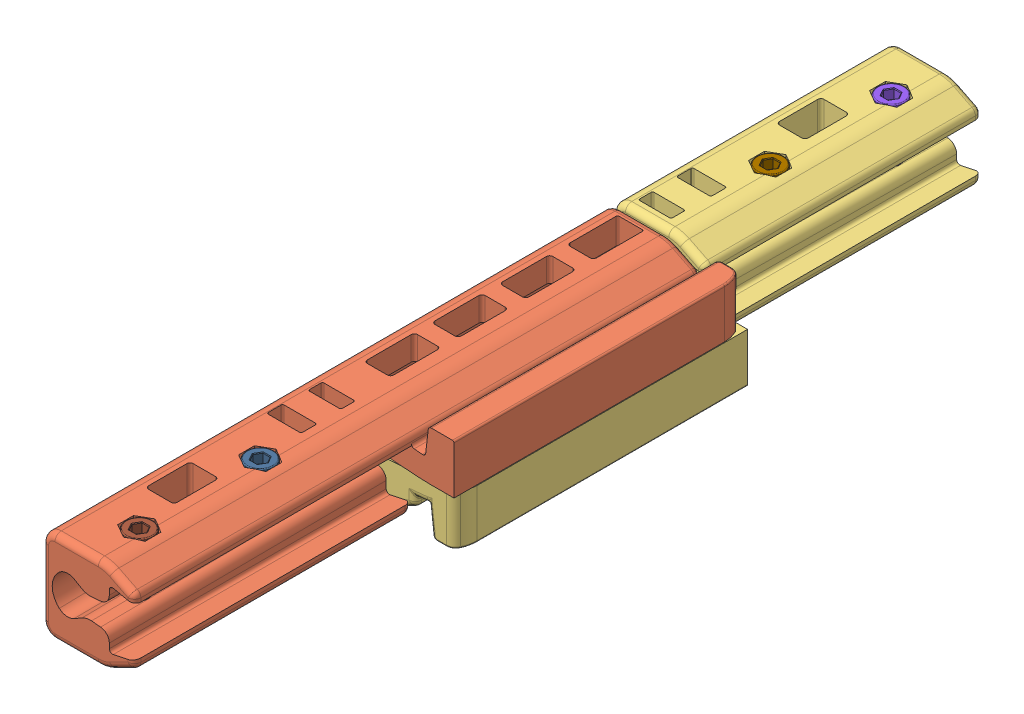
SolidWorks assembly S0737695412, configuration Default. Lengths in mm.
Overall size (43.41 31.2 267.09).
11 component instances, 11 part files, 19 mates.
Components (placement in the parent):
- 34796-CATALOGO-1: 34796-CATALOGO [Alapért.] at (4.7869 26.3916 0) size (5 5 189.3)
- 688102-1-1: 688102-1 [Alapért.] at (4.7869 26.3916 -24.7392) size (43.41 30.1 179.33)
- 688102-1_1-1: 688102-1_1 [Alapért.] at (4.7869 26.3916 0) size (43.41 30.1 179.33)
- M5-NORMALE-1: M5-NORMALE [Alapért.] at (4.7869 26.3416 -24.7392) size (8 4 9.24)
- M5-NORMALE_1-1: M5-NORMALE_1 [Alapért.] at (4.7869 26.3416 -24.7392) size (8 4 9.24)
- M5-NORMALE_2-1: M5-NORMALE_2 [Alapért.] at (4.7869 26.3916 0) size (8 4 9.24)
- M5-NORMALE_3-1: M5-NORMALE_3 [Alapért.] at (4.7869 26.3916 0) size (8 4 9.24)
- VTC_EI_M5X25_ZIN-1: VTC_EI_M5X25_ZIN [Alapért.] at (4.7869 26.3916 0) size (8.5 30 8.5)
- VTC_EI_M5X25_ZIN_1-1: VTC_EI_M5X25_ZIN_1 [Alapért.] at (4.7869 26.3916 0) size (8.5 30 8.5)
- VTC_EI_M5X25_ZIN_2-1: VTC_EI_M5X25_ZIN_2 [Alapért.] at (4.7869 26.3916 -24.7392) size (8.5 30 8.5)
- VTC_EI_M5X25_ZIN_3-1: VTC_EI_M5X25_ZIN_3 [Alapért.] at (4.7869 26.3916 -24.7392) size (8.5 30 8.5)
Mates (geometry in assembly coordinates):
- Koncentrikus1: concentric anti-aligned: cylinder of 34796-CATALOGO-1 through (14.4869 26.3916 -172.3) axis (0 0 1) radius 2.5; circle of 688102-1-1
- Koncentrikus2: concentric anti-aligned: cone of 688102-1-1 through (20.2869 16.8916 50.2608) axis (0 1 0); cylinder of VTC_EI_M5X25_ZIN_3-1 through (20.2869 35.8916 50.2608) axis (0 -1 0) radius 2.5
- Koncentrikus3: concentric anti-aligned: cone of 688102-1-1 through (20.2869 16.8916 12.2608) axis (0 1 0); cylinder of VTC_EI_M5X25_ZIN_2-1 through (20.2869 35.8916 12.2608) axis (0 -1 0) radius 2.5
- Egybeeső1: coincident aligned: plane of 688102-1-1 through (22.699 40.8916 -114.2192) normal (0 1 0); plane of VTC_EI_M5X25_ZIN_2-1 through (24.3949 40.8916 8.15) normal (0 1 0)
- Egybeeső2: coincident aligned: plane of 688102-1-1 through (22.699 40.8916 -114.2192) normal (0 1 0); plane of VTC_EI_M5X25_ZIN_3-1 through (24.3949 40.8916 46.15) normal (0 1 0)
- Egybeeső3: coincident anti-aligned: circle of M5-NORMALE-1; cylinder of VTC_EI_M5X25_ZIN_3-1 through (20.2869 35.8916 50.2608) axis (0 -1 0) radius 2.5
- Egybeeső4: coincident anti-aligned: circle of M5-NORMALE_1-1; cylinder of VTC_EI_M5X25_ZIN_2-1 through (20.2869 35.8916 12.2608) axis (0 -1 0) radius 2.5
- Távolság1: distance = 1.95 mm aligned: plane of M5-NORMALE_1-1 through (14.6043 12.8416 13.7835) normal (0 -1 0); plane of VTC_EI_M5X25_ZIN_2-1 through (22.4709 10.8916 14.4483) normal (0 -1 0)
- Távolság2: distance = 1.95 mm aligned: plane of M5-NORMALE-1 through (14.6043 12.8416 51.7835) normal (0 -1 0); plane of VTC_EI_M5X25_ZIN_3-1 through (22.4709 10.8916 52.4483) normal (0 -1 0)
- Távolság3: distance = 2 mm aligned: plane of M5-NORMALE_2-1 through (14.6043 12.8916 -146.4773) normal (0 -1 0); plane of VTC_EI_M5X25_ZIN_1-1 through (22.4709 10.8916 -145.8125) normal (0 -1 0)
- Koncentrikus4: concentric aligned: circle of M5-NORMALE_2-1; cylinder of VTC_EI_M5X25_ZIN_1-1 through (20.2869 35.8916 -148) axis (0 -1 0) radius 2.5
- Koncentrikus5: concentric aligned: circle of M5-NORMALE_3-1; cylinder of VTC_EI_M5X25_ZIN-1 through (20.2869 35.8916 -186) axis (0 -1 0) radius 2.5
- Egybeeső10: coincident aligned: plane of 688102-1_1-1 through (8.5141 40.8916 -114.34) normal (0 1 0); plane of VTC_EI_M5X25_ZIN-1 through (24.3949 40.8916 -190.1108) normal (0 1 0)
- Egybeeső11: coincident aligned: plane of 688102-1_1-1 through (8.5141 40.8916 -114.34) normal (0 1 0); plane of VTC_EI_M5X25_ZIN_1-1 through (24.3949 40.8916 -152.1108) normal (0 1 0)
- Koncentrikus7: concentric anti-aligned: cone of 688102-1_1-1 through (20.2869 23.6481 -148) axis (0 1 0); cylinder of VTC_EI_M5X25_ZIN_1-1 through (20.2869 35.8916 -148) axis (0 -1 0) radius 2.5
- Koncentrikus8: concentric anti-aligned: cone of 688102-1_1-1 through (20.2869 23.3132 -186) axis (0 1 0); cylinder of VTC_EI_M5X25_ZIN-1 through (20.2869 35.8916 -186) axis (0 -1 0) radius 2.5
- Távolság5: distance = 1 mm aligned: plane of M5-NORMALE_3-1 through (14.6043 12.8916 -184.4773) normal (0 -1 0); plane of 688102-1_1-1 through (22.699 11.8916 -21.52) normal (0 -1 0)
- Koncentrikus10: concentric anti-aligned: cylinder of 34796-CATALOGO-1 through (14.4869 26.3916 -172.3) axis (0 0 1) radius 2.5; cylinder of 688102-1_1-1 through (14.4869 26.3916 -114) axis (0 0 -1) radius 2.55
- Párhuzamos2: parallel anti-aligned: plane of 688102-1-1 through (48.0149 26.4916 -19.9192) normal (0 -1 0); plane of 688102-1_1-1 through (48.0149 26.2916 -115.82) normal (0 1 0)
